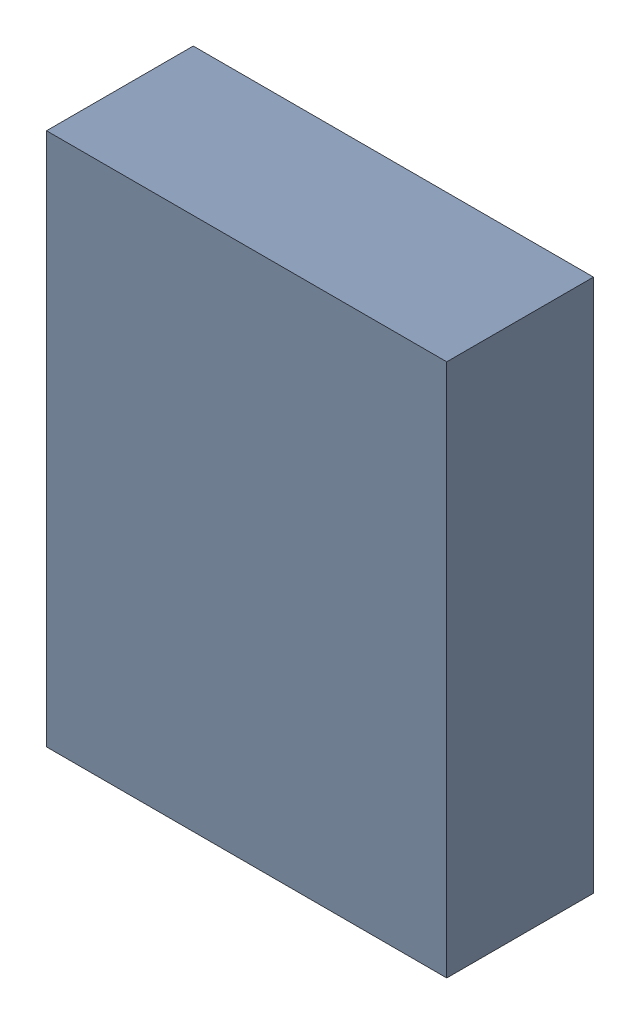
SolidWorks assembly U1, configuration Default. Lengths in mm.
Overall size (3.81 5.08 1.4).
2 component instances, 1 part files, 0 mates.
Components (placement in the parent):
- 822497696-1: 822497696 [Default] at (4.5212 6.1918 0.127) size (3.81 5.08 1.4)
  - Extruded_16-1: Extruded_16 [Default] at origin size (3.81 5.08 1.4)
